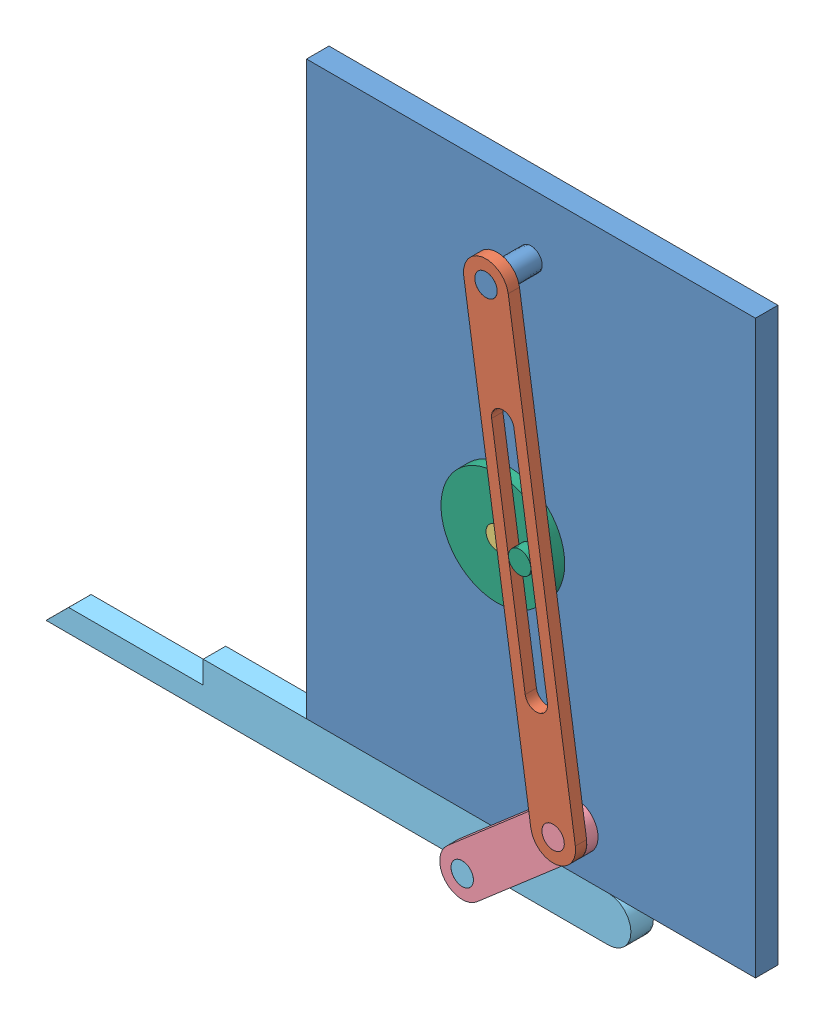
SolidWorks assembly Quick Return mechanism, configuration Default. Lengths in mm.
Overall size (630.69 556.21 60).
6 component instances, 6 part files, 15 mates.
Components (placement in the parent):
- Body-1: Body [Default] at (-0.5433 54.0854 62.9111) size (399.14 508 60)
- Slotted link-1: Slotted link [Default] at (12.8098 165.5676 112.9111) x (0.149165 -0.988812 0) z (0 0 1) size (440 40 10)
- Shaft-1: Shaft [Default] at (-0.5433 54.0854 62.9111) x (0.807787 0.589474 0) z (0 0 1) size (20 20 50)
- Middle link-1: Middle link [Default] at (13.731 -180.677 102.9111) x (0.75653 0.653959 0) z (0 0 1) size (160 40 20)
- Tool holder-1: Tool holder [Default] at (-181.6608 -219.9146 62.9111) size (520 40 50)
- Crank-2: Crank [Default] at (-0.5433 54.0854 102.9111) x (0.999024 0.044167 0) z (0 0 1) size (100 100 20)
Mates (geometry in assembly coordinates):
- Concentric1: concentric aligned: cylinder of Body-1 through (-0.5433 54.0854 82.9111) axis (0 0 -1) radius 10; cylinder of Shaft-1 through (-0.5433 54.0854 112.9111) axis (0 0 -1) radius 10
- Coincident1: coincident anti-aligned: circle of Body-1; cylinder of Shaft-1 through (-0.5433 54.0854 112.9111) axis (0 0 -1) radius 10
- Coincident2: coincident anti-aligned: plane of Body-1 through (-0.5433 54.0854 62.9111) normal (0 0 -1); circle of Shaft-1
- Coincident3: coincident anti-aligned: cylinder of Body-1 through (-0.5433 254.0854 122.9111) axis (0 0 -1) radius 10; circle of Slotted link-1
- Coincident4: coincident aligned: circle of Body-1; plane of Slotted link-1 through (-0.5433 254.0854 122.9111) normal (0 0 1)
- Coincident7: coincident anti-aligned: cylinder of Shaft-1 through (-0.5433 54.0854 112.9111) axis (0 0 -1) radius 10; circle of Crank-2
- Coincident8: coincident aligned: circle of Shaft-1; plane of Crank-2 through (-0.5433 54.0854 112.9111) normal (0 0 1)
- Lock2: lock: unknown of Shaft-1; unknown of Crank-2
- Tangent3: tangent anti-aligned: plane of Slotted link-1 through (-5.0077 153.6859 122.9111) normal (-0.989635 0.143607 0); cylinder of Crank-2 through (-30.2114 49.6349 122.9111) axis (0 0 -1) radius 10
- Concentric2: concentric aligned: cylinder of Slotted link-1 through (-57.9861 -141.7685 122.9111) axis (0 0 -1) radius 10; cylinder of Middle link-1 through (-57.9861 -141.7685 122.9111) axis (0 0 -1) radius 10
- Coincident9: coincident anti-aligned: plane of Slotted link-1 through (-0.5433 254.0854 112.9111) normal (0 0 -1); plane of Middle link-1 through (-149.0531 -219.9146 112.9111) normal (0 0 1)
- Concentric3: concentric aligned: cylinder of Middle link-1 through (-149.0531 -219.9146 112.9111) axis (0 0 -1) radius 10; cylinder of Tool holder-1 through (-149.0531 -219.9146 112.9111) axis (0 0 -1) radius 10
- Coincident10: coincident aligned: plane of Middle link-1 through (-149.0531 -219.9146 112.9111) normal (0 0 1); plane of Tool holder-1 through (-149.0531 -219.9146 112.9111) normal (0 0 1)
- Parallel3: parallel anti-aligned: plane of Body-1 through (-200.1152 -199.9146 82.9111) normal (0 -1 0); plane of Tool holder-1 through (-409.3363 -199.9146 82.9111) normal (0 1 0)
- Coincident11: coincident anti-aligned: plane of Body-1 through (-200.1152 -199.9146 82.9111) normal (0 -1 0); plane of Tool holder-1 through (-409.3363 -199.9146 82.9111) normal (0 1 0)
